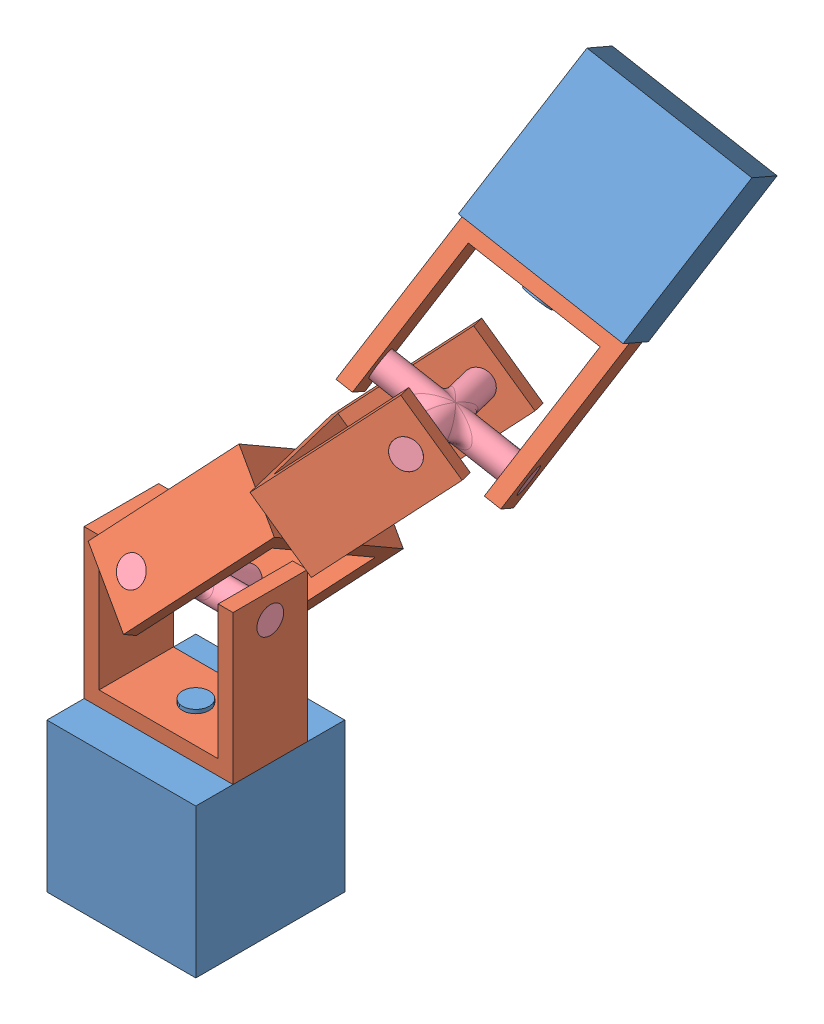
SolidWorks assembly lab8, configuration Default. Lengths in mm.
Overall size (63.34 120.19 75.65).
9 component instances, 4 part files, 22 mates.
Components (placement in the parent):
- Post-1: Post [Default] at origin size (25.4 28.57 25.4)
- Post-2: Post [Default] at (31.5172 85.8076 -40.4351) x (0.492129 0.565332 0.661973) z (0.856155 -0.451909 -0.250555) size (25.4 28.57 25.4)
- Pivot-1: Pivot [Default] at (13.0962 48.143 -8.2767) x (-0.784242 0.53733 -0.310228) z (0 0.5 0.866025) size (12.7 25.4 25.4)
- Pivot-2: Pivot [Default] at (0 12.7 0) x (0 0 1) z (-1 0 0) size (12.7 25.4 25.4)
- Pivot-3: Pivot [Default] at (29.5169 77.0439 -31.4638) x (0.492129 0.565332 0.661973) z (0.856155 -0.451909 -0.250555) size (12.7 25.4 25.4)
- Pivot-4: Pivot [Default] at (13.0962 48.143 -8.2767) x (-0.693078 0.708843 0.13109) z (-0.366985 -0.190435 -0.910526) size (12.7 25.4 25.4)
- Rivet-1: Rivet [Default] at (10.7323 45.5553 -6.7827) x (-0.782811 0.566541 -0.257369) z (0.047355 0.466642 0.883178) size (7.62 7.62 7.62)
- Swivel-1: Swivel [Default] at (0 33.8074 0) x (1 0 0) z (0 0.5 0.866025) size (25.4 4.57 25.4)
- Swivel-2: Swivel [Default] at (26.1924 62.4786 -16.5533) x (0.856155 -0.451909 -0.250555) z (-0.366985 -0.190435 -0.910526) size (25.4 4.57 25.4)
Mates (geometry in assembly coordinates):
- Concentric1: concentric aligned: circle of Post-1; circle of Pivot-2
- Coincident1: coincident anti-aligned: plane of Post-1 through (0 12.7 0) normal (0 1 0); plane of Pivot-2 through (-12.7 12.7 6.35) normal (0 -1 0)
- Parallel1: parallel anti-aligned: line of Post-1 through (-12.7 12.7 12.7) axis (1 0 0); line of Pivot-2 through (12.7 12.7 6.35) axis (-1 0 0)
- Concentric2: concentric aligned: circle of Post-2; circle of Pivot-3
- Coincident2: coincident anti-aligned: plane of Post-2 through (29.5169 77.0439 -31.4638) normal (-0.157505 -0.690057 0.706409); plane of Pivot-3 through (43.5151 74.8945 -30.4423) normal (0.157505 0.690057 -0.706409)
- Parallel2: parallel anti-aligned: line of Post-2 through (46.6401 78.4843 -26.2387) axis (-0.856155 0.451909 0.250555); line of Pivot-3 through (21.7688 86.373 -24.0782) axis (0.856155 -0.451909 -0.250555)
- Concentric3: concentric aligned: cylinder of Pivot-2 through (12.7 33.8074 0) axis (-1 0 0) radius 2.286; cylinder of Swivel-1 through (12.7 33.8074 0) axis (-1 0 0) radius 2.286
- Coincident3: coincident aligned: plane of Pivot-2 through (12.7 12.7 6.35) normal (1 0 0); plane of Swivel-1 through (12.7 33.8074 0) normal (1 0 0)
- Concentric4: concentric anti-aligned: circle of Pivot-3; cylinder of Swivel-2 through (37.0656 56.7393 -19.7353) axis (-0.856155 0.451909 0.250555) radius 2.286
- Coincident4: coincident aligned: plane of Pivot-3 through (43.5151 74.8945 -30.4423) normal (0.856155 -0.451909 -0.250555); plane of Swivel-2 through (37.0656 56.7393 -19.7353) normal (0.856155 -0.451909 -0.250555)
- Concentric5: concentric aligned: cylinder of Pivot-1 through (13.0962 48.143 -8.2767) axis (-0.620456 -0.679173 0.392121) radius 2.286; cylinder of Rivet-1 through (10.7323 45.5553 -6.7827) axis (-0.620456 -0.679173 0.392121) radius 2.286
- Coincident5: coincident anti-aligned: plane of Pivot-1 through (6.5403 56.1799 1.7479) normal (-0.620456 -0.679173 0.392121); plane of Rivet-1 through (11.412 45.3511 -9.2996) normal (0.620456 0.679173 -0.392121)
- Concentric6: concentric anti-aligned: cylinder of Pivot-4 through (13.0962 48.143 -8.2767) axis (0.620456 0.679173 -0.392121) radius 2.286; cylinder of Rivet-1 through (10.7323 45.5553 -6.7827) axis (-0.620456 -0.679173 0.392121) radius 2.286
- Coincident6: coincident anti-aligned: plane of Pivot-4 through (5.6104 51.9507 -20.0039) normal (0.620456 0.679173 -0.392121); plane of Rivet-1 through (14.4917 48.0902 -12.6375) normal (-0.620456 -0.679173 0.392121)
- Concentric7: concentric anti-aligned: cylinder of Pivot-1 through (0 27.4574 -10.9985) axis (0 0.5 0.866025) radius 2.286; cylinder of Swivel-1 through (0 40.1574 10.9985) axis (0 -0.5 -0.866025) radius 2.286
- Coincident7: coincident aligned: plane of Pivot-1 through (8.1163 57.905 0.7519) normal (0 0.5 0.866025); plane of Swivel-1 through (0 40.1574 10.9985) normal (0 0.5 0.866025)
- Concentric8: concentric anti-aligned: cylinder of Pivot-4 through (30.8531 64.8971 -4.9896) axis (-0.366985 -0.190435 -0.910526) radius 2.286; cylinder of Swivel-2 through (21.5317 60.06 -28.117) axis (0.366985 0.190435 0.910526) radius 2.286
- Coincident8: coincident aligned: plane of Pivot-4 through (13.3559 55.0627 4.1194) normal (0.366985 0.190435 0.910526); plane of Swivel-2 through (30.8531 64.8971 -4.9896) normal (0.366985 0.190435 0.910526)
- Parallel3: parallel aligned: plane of Post-1 through (-12.7 12.7 12.7) normal (-1 0 0); plane of Pivot-2 through (-12.7 12.7 6.35) normal (-1 0 0)
- Angle6: planar angle = 0.523599 rad aligned: plane of Pivot-1 through (8.1163 57.905 0.7519) normal (0 0.5 0.866025); plane of Pivot-2 through (0 12.7 6.35) normal (0 0 1)
- Parallel4: parallel aligned: plane of Post-2 through (12.3937 75.6034 -36.6888) normal (-0.856155 0.451909 0.250555); plane of Pivot-3 through (21.7688 86.373 -24.0782) normal (-0.856155 0.451909 0.250555)
- Angle9: planar angle = 0.471239 rad aligned: plane of Pivot-4 through (13.3559 55.0627 4.1194) normal (0.366985 0.190435 0.910526); plane of Pivot-3 through (32.642 80.6337 -27.2602) normal (0.492129 0.565332 0.661973)
